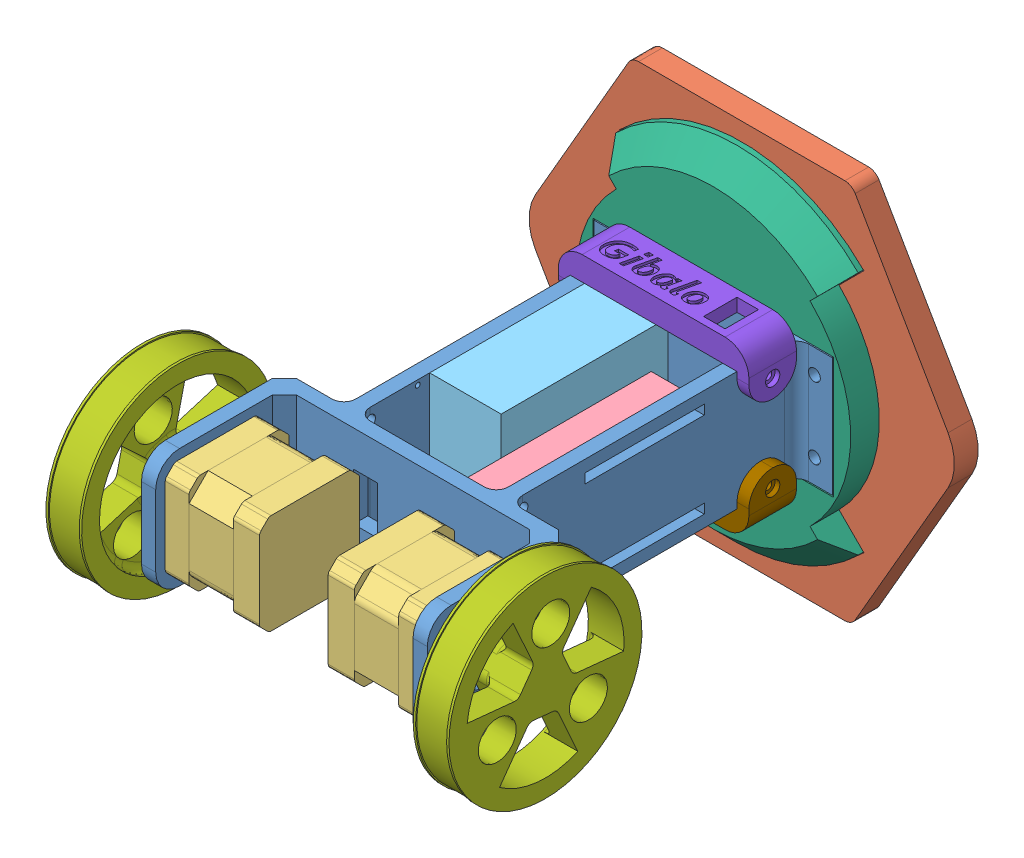
SolidWorks assembly GibaloV2, configuration Default. Lengths in mm.
Overall size (178.56 160 234.25).
11 component instances, 9 part files, 28 mates.
Components (placement in the parent):
- Framev2-1: Framev2 [Default] at (52.1135 168.3292 78.235) x (1 0 0) z (0 0.000022 1) size (120 50 185)
- top_plainv2-1: top_plainv2 [Default] at (52.1135 193.3256 -88.7655) x (1 0 0) z (0 1 -0.000022) size (178.56 10 160)
- nema17-3: nema17 [Default] at (96.1135 193.3292 78.2345) x (0 -1 0.000022) z (0 0.000022 1) size (42 64.2 42.5)
- nema17-2: nema17 [Default] at (8.1135 193.3292 78.2345) x (0 1 -0.000022) z (0 0.000022 1) size (42 64.2 42.5)
- batteryv2-1: batteryv2 [Default] at (81.1135 193.8277 5.3773) x (0 0.000022 1) z (0 -1 0.000022) size (80 20 33)
- electronics-2: electronics [Default] at (53.1135 199.4272 -4.3871) x (0 0.000022 1) z (0 -1 0.000022) size (70 30 50)
- acc_holdv2-2: acc_holdv2 [Default] at (55.5423 190.584 -76.7655) x (1 0 0) z (0 -0.000022 -1) size (115.5 144.5 21)
- Wheel4-3: Wheel4 [Default] at (136.7135 193.3292 78.2345) x (0 0.911544 0.411202) z (0 -0.411202 0.911544) size (81 20 81)
- Wheel4-2: Wheel4 [Default] at (-32.4865 193.3292 78.2345) x (0 -0.683719 -0.729745) z (0 -0.729745 0.683719) size (81 20 81)
- bluetooth_mount-1: bluetooth_mount [Default] at (51.1382 223.636 -51.7662) x (1 0 0) z (0 1 -0.000022) size (80 20 22.5)
- labmehsus-1: labmehsus [Default] at (53.0887 163.0168 -51.7649) x (-1 0 0) z (0 -1 0.000022) size (80 20 22.5)
Mates (geometry in assembly coordinates):
- Coincident16: coincident anti-aligned: plane of Framev2-1 through (81.1135 168.3259 -76.765) normal (-1 0 0); plane of batteryv2-1 through (81.1135 193.8277 5.3773) normal (1 0 0)
- Coincident17: coincident aligned: plane of Framev2-1 through (69.1135 177.3278 11.973) normal (0 -1 0.000022); plane of batteryv2-1 through (61.1135 177.3266 -41.7652) normal (0 -1 0.000022)
- Coincident20: coincident anti-aligned: plane of Framev2-1 through (23.1135 168.3259 -76.765) normal (1 0 0); plane of electronics-2 through (23.1135 199.4272 -4.3871) normal (-1 0 0)
- Coincident21: coincident aligned: plane of Framev2-1 through (52.1135 218.3292 78.2339) normal (0 1 -0.000022); plane of electronics-2 through (23.1135 218.3278 13.2339) normal (0 1 -0.000022)
- Distance7: distance = 0.5 mm: line of Framev2-1 through (92.1135 218.3259 -76.7661) axis (1 0 0); line of acc_holdv2-2 through (102.6135 218.8259 -76.7661) axis (-1 0 0)
- Coincident34: coincident aligned: plane of top_plainv2-1 through (52.1135 193.3254 -97.7655) normal (0 -0.000022 -1); plane of acc_holdv2-2 through (52.1135 151.3254 -97.7646) normal (0 -0.000022 -1)
- Distance6: distance = 0.5 mm: line of Framev2-1 through (2.1135 168.3258 -81.765) axis (0 1 -0.000022); line of acc_holdv2-2 through (1.6135 218.8258 -81.7661) axis (0 -1 0.000022)
- Concentric17: concentric anti-aligned: circle of top_plainv2-1; circle of acc_holdv2-2
- Distance4: distance = 30 mm anti-aligned: plane of electronics-2 through (23.1135 168.3278 13.235) normal (0 0.000022 1); plane of Framev2-1 through (-7.8865 218.3285 43.2339) normal (0 -0.000022 -1)
- Distance5: distance = 5 mm anti-aligned: plane of batteryv2-1 through (61.1135 210.3284 38.2341) normal (0 0.000022 1); plane of Framev2-1 through (-7.8865 218.3285 43.2339) normal (0 -0.000022 -1)
- Coincident60: coincident anti-aligned: plane of Framev2-1 through (52.1135 168.3258 -81.765) normal (0 -0.000022 -1); plane of acc_holdv2-2 through (55.5423 190.5839 -81.7655) normal (0 0.000022 1)
- Parallel1: parallel anti-aligned: plane of Framev2-1 through (-1.8865 218.3286 49.2339) normal (0 0.000022 1); plane of nema17-2 through (-1.8865 172.3288 57.2349) normal (0 -0.000022 -1)
- Concentric20: concentric anti-aligned: circle of Framev2-1; circle of nema17-2
- Coincident73: coincident anti-aligned: plane of Framev2-1 through (-1.8865 218.3286 49.2339) normal (1 0 0); plane of nema17-2 through (-1.8865 193.3292 78.2345) normal (-1 0 0)
- Coincident74: coincident anti-aligned: plane of Framev2-1 through (106.1135 218.3286 49.2339) normal (-1 0 0); plane of nema17-3 through (106.1135 193.3292 78.2345) normal (1 0 0)
- Parallel2: parallel anti-aligned: plane of Framev2-1 through (-1.8865 218.3286 49.2339) normal (0 0.000022 1); plane of nema17-3 through (106.1135 214.3288 57.234) normal (0 -0.000022 -1)
- Concentric21: concentric anti-aligned: circle of Framev2-1; circle of nema17-3
- Concentric22: concentric aligned: cylinder of nema17-2 through (-26.4865 193.3292 78.2345) axis (1 0 0) radius 2.5; circle of Wheel4-2
- Concentric23: concentric aligned: cylinder of nema17-3 through (130.7135 193.3292 78.2345) axis (-1 0 0) radius 2.5; circle of Wheel4-3
- Coincident76: coincident anti-aligned: plane of nema17-2 through (-26.4865 193.3292 78.2345) normal (-1 0 0); plane of Wheel4-2 through (-26.4865 193.3292 78.2345) normal (1 0 0)
- Coincident77: coincident anti-aligned: plane of nema17-3 through (130.7135 193.3292 78.2345) normal (1 0 0); plane of Wheel4-3 through (130.7135 193.3292 78.2345) normal (-1 0 0)
- Coincident79: coincident anti-aligned: plane of Framev2-1 through (52.1135 218.3292 78.2339) normal (0 1 -0.000022); plane of bluetooth_mount-1 through (51.1382 218.326 -71.7661) normal (0 -1 0.000022)
- Concentric24: concentric anti-aligned: cylinder of Framev2-1 through (92.1135 213.3262 -61.766) axis (-1 0 0) radius 2.25; cylinder of bluetooth_mount-1 through (-1.8865 213.3262 -61.766) axis (1 0 0) radius 1.6
- Coincident80: coincident anti-aligned: plane of Framev2-1 through (87.1135 168.3259 -76.765) normal (1 0 0); plane of bluetooth_mount-1 through (87.1135 223.6356 -71.7662) normal (-1 0 0)
- Concentric27: concentric aligned: cylinder of top_plainv2-1 through (94.6135 178.3258 -77.7652) axis (0 -0.000022 -1) radius 2; cylinder of acc_holdv2-2 through (94.6135 178.3263 -57.7652) axis (0 -0.000022 -1) radius 2
- Concentric28: concentric aligned: cylinder of Framev2-1 through (92.1135 173.3262 -61.7651) axis (-1 0 0) radius 2.25; cylinder of labmehsus-1 through (106.1135 173.3262 -61.7651) axis (-1 0 0) radius 1.6
- Coincident82: coincident anti-aligned: plane of Framev2-1 through (52.1135 168.3292 78.235) normal (0 -1 0.000022); plane of labmehsus-1 through (53.0887 168.326 -71.765) normal (0 1 -0.000022)
- Coincident83: coincident anti-aligned: plane of Framev2-1 through (87.1135 168.3259 -76.765) normal (1 0 0); plane of labmehsus-1 through (87.1135 163.0164 -71.7649) normal (-1 0 0)
